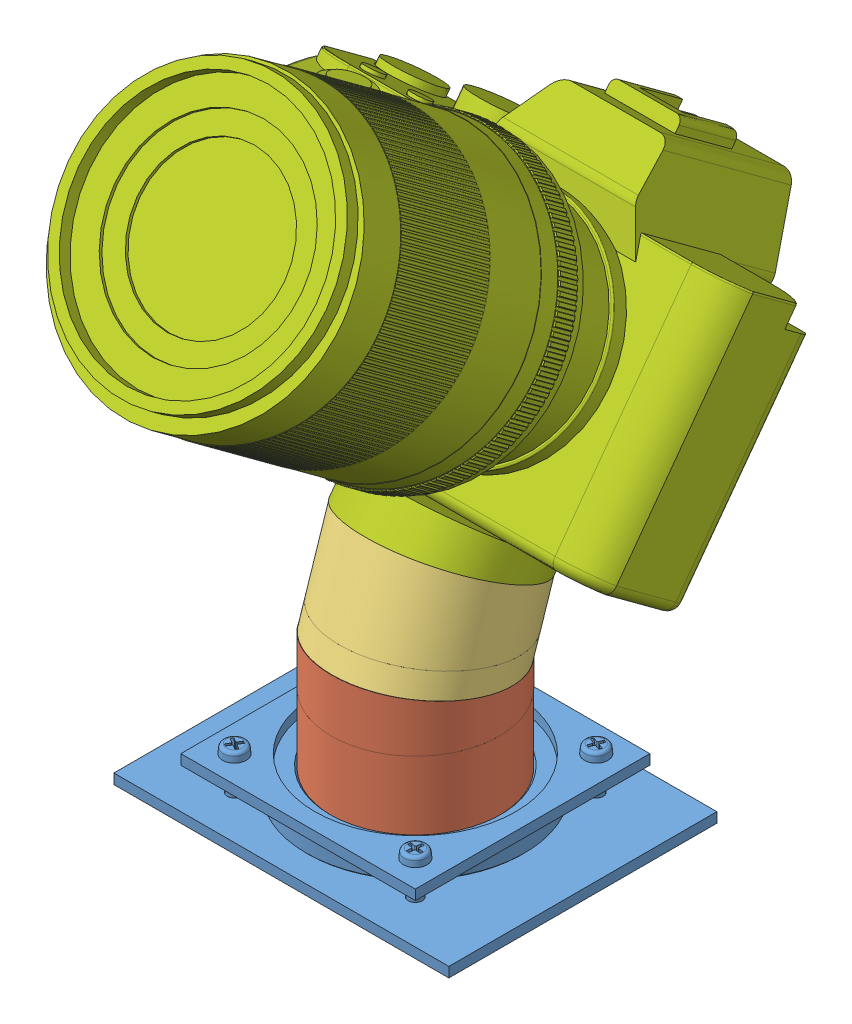
SolidWorks assembly sim, configuration 默认. Lengths in mm.
Overall size (132.15 240.23 199.01).
7 component instances, 7 part files, 15 mates.
Components (placement in the parent):
- basep-1: basep [默认] at (-5.3872 -4.1266 0) size (100 18.6 80)
- bar1p-1: bar1p [默认] at (4.2929 10.4677 150) x (-1 0 0) z (0 0 -1) size (50 45.82 50)
- bar2p-1: bar2p [默认] at (-2.4832 46.4344 147.3596) x (1 0 0) z (0 -0.312033 -0.950071) size (50 40.91 50)
- bar23-1: bar23 [默认] at (1.5993 33.771 99.4046) x (-0.997626 -0.011958 -0.067818) z (0.068864 -0.173236 -0.98247) size (30 17 30)
- motor2-1: motor2 [默认] at (1.5993 -22.4057 100) x (-0.158953 0 -0.987286) z (0.987286 0 -0.158953) size (36 40 36)
- motor3-1: motor3 [默认] at (1.5993 -27.8135 100) x (0.38474 0 0.923025) z (-0.923025 0 0.38474) size (20.5 50 20.5)
- bar3p-1: bar3p [默认] at (-48.4007 55.0972 94.6829) x (0 -0.592907 -0.805271) z (1 0 0) size (164 112.91 132.15)
Mates (geometry in assembly coordinates):
- 同心1: concentric aligned: cylinder of basep-1 through (1.5993 -1.0138 100) axis (0 -1 0) radius 32.5; cylinder of bar1p-1 through (1.5993 18.9862 100) axis (0 -1 0) radius 25
- 重合1: coincident aligned: plane of basep-1 through (1.5993 -11.0138 100) normal (0 -1 0); plane of bar1p-1 through (1.5993 -11.0138 100) normal (0 -1 0)
- 同心2: concentric aligned: cylinder of bar1p-1 through (1.5993 23.5007 101.2155) axis (0 0.984808 -0.173648) radius 21; cylinder of bar2p-1 through (1.5993 23.5007 101.2155) axis (0 0.984808 -0.173648) radius 21
- 重合2: coincident anti-aligned: plane of bar1p-1 through (1.5993 23.5007 101.2155) normal (0 0.984808 -0.173648); plane of bar2p-1 through (1.5993 23.5007 101.2155) normal (0 -0.984808 0.173648)
- 同心3: concentric anti-aligned: cylinder of bar2p-1 through (1.5993 33.771 99.4046) axis (0 0.984808 -0.173648) radius 15; cylinder of bar23-1 through (1.5993 40.6647 98.1891) axis (0 -0.984808 0.173648) radius 15
- 重合3: coincident aligned: plane of bar2p-1 through (1.5993 40.6647 98.1891) normal (0 0.984808 -0.173648); plane of bar23-1 through (1.5993 40.6647 98.1891) normal (0 0.984808 -0.173648)
- 同心4: concentric aligned: cylinder of basep-1 through (1.5993 -1.0138 100) axis (0 -1 0) radius 32.5; cylinder of motor2-1 through (1.5993 17.5943 100) axis (0 -1 0) radius 17
- 距离1: distance = 11.3919 mm aligned: plane of motor2-1 through (1.5993 -22.4057 100) normal (0 -1 0); plane of basep-1 through (1.5993 -11.0138 100) normal (0 -1 0)
- 同心5: concentric aligned: cylinder of basep-1 through (1.5993 -1.0138 100) axis (0 -1 0) radius 32.5; cylinder of motor3-1 through (1.5993 22.1865 100) axis (0 -1 0) radius 9.5
- 距离2: distance = 16.7997 mm aligned: plane of motor3-1 through (1.5993 -27.8135 100) normal (0 -1 0); plane of basep-1 through (1.5993 -11.0138 100) normal (0 -1 0)
- 同心6: concentric aligned: cylinder of bar2p-1 through (1.5993 47.8735 95.3039) axis (0 0.895994 -0.444066) radius 15; cylinder of bar3p-1 through (1.5993 47.8735 95.3039) axis (0 0.895994 -0.444066) radius 15
- 重合8: coincident anti-aligned: plane of bar2p-1 through (1.5993 54.1455 92.1954) normal (0 0.895994 -0.444066); plane of bar3p-1 through (-39.4007 65.4184 114.9408) normal (0 -0.895994 0.444066)
- 齿轮配合1: gear = 34 : 34 mm: cylinder of motor2-1 through (1.5993 17.5943 100) axis (0 -1 0) radius 17; cylinder of bar2p-1 through (1.5993 20.5463 101.7365) axis (0 0.984808 -0.173648) radius 17
- 齿轮配合2: gear = 20 : 20 mm: cylinder of motor3-1 through (1.5993 22.1865 100) axis (0 -1 0) radius 9.5; cylinder of bar23-1 through (1.5993 23.923 101.1411) axis (0 0.984808 -0.173648) radius 10
- 齿轮配合3: gear = 30 : 30 mm: cylinder of bar23-1 through (1.5993 40.6647 98.1891) axis (0 -0.984808 0.173648) radius 15; cylinder of bar3p-1 through (1.5993 47.8735 95.3039) axis (0 0.895994 -0.444066) radius 15
